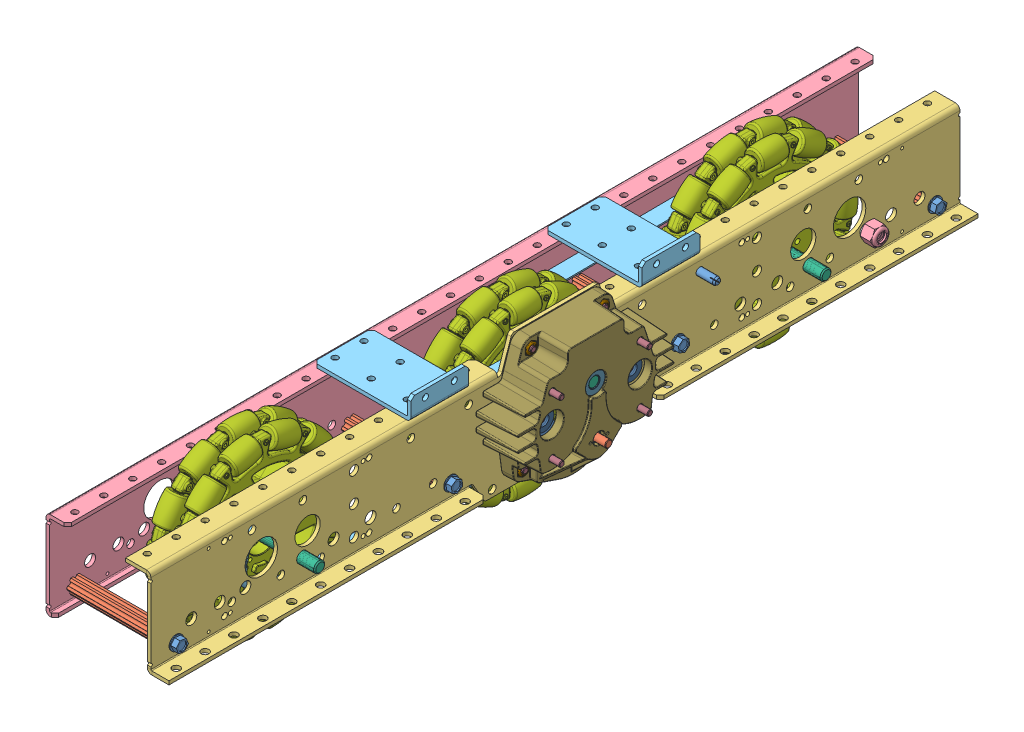
SolidWorks assembly Square half 2, configuration Default. Lengths in mm.
Overall size (145.24 217.11 711.33).
59 component instances, 25 part files, 19 mates.
Components (placement in the parent):
- AM14U3Square_Frame_Half-1: AM14U3Square_Frame_Half [Default] at (326.068 37.2757 -291.2758) size (113.54 116.33 711.33)
  - ThreadRollingScrew_0.25-20x0.75-1: ThreadRollingScrew_0.25-20x0.75 [FHTS 0.25-20-G-0.75-C] at (-758.825 -67.437 692.15) x (-1 0 0) z (0 0.924225 0.381849) size (24.64 12.19 12.19)
  - ThreadRollingScrew_0.25-20x0.75-4: ThreadRollingScrew_0.25-20x0.75 [FHTS 0.25-20-G-0.75-C] at (-758.825 -67.437 25.146) x (-1 0 0) z (0 0.717495 0.696564) size (24.64 12.19 12.19)
  - ThreadRollingScrew_0.25-20x0.75-5: ThreadRollingScrew_0.25-20x0.75 [FHTS 0.25-20-G-0.75-C] at (-850.9 -67.437 25.4) size (24.64 12.19 12.19)
  - ThreadRollingScrew_0.25-20x0.75-7: ThreadRollingScrew_0.25-20x0.75 [FHTS 0.25-20-G-0.75-C] at (-762 -15.24 231.648) x (1 0 0) z (0 0.687398 0.726281) size (24.64 12.19 12.19)
  - ThreadRollingScrew_0.25-20x0.75-9: ThreadRollingScrew_0.25-20x0.75 [FHTS 0.25-20-G-0.75-C] at (-850.9 -67.437 692.15) size (24.64 12.19 12.19)
  - 500Churro_3.375-1: 500Churro_3.375 [Default] at (-762 -67.437 25.4) x (0 -0.866025 0.5) z (-1 0 0) size (14.66 12.7 85.72)
  - 500Churro_3.375-2: 500Churro_3.375 [Default] at (-762 -67.437 692.15) x (0 -0.866025 0.5) z (-1 0 0) size (14.66 12.7 85.72)
  - AM14U3InnerPlate_Square-1: AM14U3InnerPlate_Square [Default] at (-762 -76.962 765.048) x (0 0 -1) z (0 -1 0) size (711.2 38.1 116.33)
  - AM14U3OuterPlate_Square-1: AM14U3OuterPlate_Square [Default] at (-826.4985 -26.7681 74.8245) x (0 0 1) z (0 -1 0) size (711.2 19.05 77.72)
  - Bracket_2x3-1: Bracket_2x3 [Default] at (-844.55 -3.175 498.348) size (85.72 19.05 50.8)
  - Bracket_2x3-2: Bracket_2x3 [Default] at (-844.55 -3.175 295.148) size (85.72 19.05 50.8)
  - 500Churro_3.375-5: 500Churro_3.375 [Default] at (-847.725 -66.675 450.723) x (0 0 -1) z (1 0 0) size (14.66 12.7 85.72)
  - 500Churro_3.375-6: 500Churro_3.375 [Default] at (-847.725 -59.4147 251.1225) x (0 0.13828 0.990393) z (1 0 0) size (14.66 12.7 85.72)
  - ThreadRollingScrew_0.25-20x0.75-11: ThreadRollingScrew_0.25-20x0.75 [FHTS 0.25-20-G-0.75-C] at (-758.825 -66.675 450.723) x (-1 0 0) z (0 0.997671 0.06821) size (24.64 12.19 12.19)
  - ThreadRollingScrew_0.25-20x0.75-12: ThreadRollingScrew_0.25-20x0.75 [FHTS 0.25-20-G-0.75-C] at (-758.825 -59.4147 251.1225) x (-1 0 0) z (0 -0.62596 0.779855) size (24.64 12.19 12.19)
  - ThreadRollingScrew_0.25-20x0.75-13: ThreadRollingScrew_0.25-20x0.75 [FHTS 0.25-20-G-0.75-C] at (-850.9 -66.675 450.85) size (24.64 12.19 12.19)
  - ThreadRollingScrew_0.25-20x0.75-14: ThreadRollingScrew_0.25-20x0.75 [FHTS 0.25-20-G-0.75-C] at (-850.9 -66.675 266.7) size (24.64 12.19 12.19)
- ToughboxMini-1: ToughboxMini [Default] at (-483.2987 -32.4844 158.473) x (0 0.001296 0.999999) z (-1 0 0) size (140.05 118.73 142.29) (flexible)
  - TBMiniSmallHexShaft-1: TBMiniSmallHexShaft [Default] at (-129.0775 70.1149 -52.3959) x (-0.997833 0.06579 0) z (0.06579 0.997833 0) size (11 38.23 9.52)
  - LargeClusterGear_Hex_50t0.375-1: LargeClusterGear_Hex_50t0.375 [Default] at (-91.0349 50.9043 -67.5597) x (-0.997833 0.06579 0) z (0 0 -1) size (65.97 66.04 10.16)
  - Bearing_FR6ZZ-1: Bearing_FR6ZZ [Default] at (-96.247 60.278 -52.5991) x (-0.893862 0.448342 0) z (0 0 1) size (24.69 24.69 7.16)
  - NylockNut_10-32-1: NylockNut_10-32 [Default] at (-129.8464 -8.0737 -56.3837) x (0.501678 0.865055 0) z (0 0 -1) size (10.18 11.01 7.1)
  - NylockNut_10-32-2: NylockNut_10-32 [Default] at (-59.2462 80.7349 -56.3837) x (0.999999 -0.001296 0) z (0 0 -1) size (10.18 11.01 7.1)
  - NylockNut_10-32-3: NylockNut_10-32 [Default] at (-122.7461 80.8172 -56.3837) x (0.500567 0.865698 0) z (0 0 -1) size (10.18 11.01 7.1)
  - NylockNut_10-32-4: NylockNut_10-32 [Default] at (-52.3764 -8.1741 -56.3837) x (-0.501678 -0.865055 0) z (0 0 -1) size (10.18 11.01 7.1)
  - Washer_5-16-1: Washer_5-16 [Default] at (-52.3162 38.3079 -77.7705) x (-0.418041 0.908428 0) z (0 0 -1) size (17.53 17.53 1.47)
  - Washer_5-16-2: Washer_5-16 [Default] at (-52.3162 38.3079 -76.2973) x (0.897267 -0.441488 0) z (0 0 -1) size (17.53 17.53 1.47)
  - Washer_5-16-3: Washer_5-16 [Default] at (-129.7861 38.4083 -77.7705) x (-0.990116 0.140253 0) z (0 0 1) size (17.53 17.53 1.47)
  - Washer_5-16-4: Washer_5-16 [Default] at (-129.7861 38.4083 -79.2437) x (-0.681761 0.731575 0) z (0 0 1) size (17.53 17.53 1.47)
  - CIMGear_14t8mm-1: CIMGear_14t8mm [Default] at (-52.3162 38.3079 -63.5973) x (0.300324 0.953837 0) z (0 0 -1) size (20.03 20.32 12.7)
  - CIMGear_14t8mm-2: CIMGear_14t8mm [Default] at (-129.7861 38.4083 -63.5973) x (0.860119 0.510093 0) z (0 0 -1) size (20.03 20.32 12.7)
  - TBMiniHousing-1: TBMiniHousing [Default] at (-91.0876 10.1882 -86.3557) x (0.999999 -0.001296 0) z (0 0 1) size (139.9 118.55 41.54)
  - Screw_SHCS_10-32x0.625-1: Screw_SHCS_10-32x0.625 [Default] at (-52.2832 63.7078 -74.4685) x (-0.564778 -0.825243 0) z (-0.825243 0.564778 0) size (7.82 20.65 7.82)
  - Screw_SHCS_10-32x0.625-2: Screw_SHCS_10-32x0.625 [Default] at (-122.7461 80.8172 -42.5915) x (0.507484 -0.861661 0) z (-0.861661 -0.507484 0) size (7.82 20.65 7.82)
  - Screw_SHCS_10-32x0.625-3: Screw_SHCS_10-32x0.625 [Default] at (-52.3764 -8.1741 -42.5915) x (0.507484 -0.861661 0) z (-0.861661 -0.507484 0) size (7.82 20.65 7.82)
  - Screw_SHCS_10-32x0.625-4: Screw_SHCS_10-32x0.625 [Default] at (-129.8464 -8.0737 -42.5915) x (0.507484 -0.861661 0) z (-0.861661 -0.507484 0) size (7.82 20.65 7.82)
  - Screw_SHCS_10-32x0.625-5: Screw_SHCS_10-32x0.625 [Default] at (-59.2462 80.7349 -42.5915) x (0.740711 -0.671824 0) z (-0.671824 -0.740711 0) size (7.82 20.65 7.82)
  - Screw_SHCS_10-32x0.625-6: Screw_SHCS_10-32x0.625 [Default] at (-52.3491 12.9079 -74.4685) x (-0.564778 -0.825243 0) z (-0.825243 0.564778 0) size (7.82 20.65 7.82)
  - Screw_SHCS_10-32x0.625-7: Screw_SHCS_10-32x0.625 [Default] at (-129.7532 63.8083 -74.4685) x (-0.966277 -0.257503 0) z (-0.257503 0.966277 0) size (7.82 20.65 7.82)
  - Screw_SHCS_10-32x0.625-8: Screw_SHCS_10-32x0.625 [Default] at (-129.819 13.0083 -74.4685) x (-0.99652 0.083357 0) z (0.083357 0.99652 0) size (7.82 20.65 7.82)
  - Bearing_R6ZZ-3: Bearing_R6ZZ [Default] at (-91.0349 50.9043 -84.8317) x (0.958138 -0.286306 0) z (0 0 1) size (22.23 22.23 7.11)
  - Bearing_R6ZZ-4: Bearing_R6ZZ [Default] at (-91.0876 10.1882 -84.8317) x (-0.661529 0.74992 0) z (0 0 1) size (22.23 22.23 7.11)
  - RetainingClip-1: RetainingClip [Default] at (-129.7861 38.4083 -63.5973) x (0 0 1) z (-1 0 0) size (1.09 14.83 14.83)
  - RetainingClip-2: RetainingClip [Default] at (-52.3162 38.3079 -63.5973) x (0 0 1) z (-1 0 0) size (1.09 14.83 14.83)
  - ExternalKlipring-1: ExternalKlipring [Default] at (-91.0876 10.1882 -64.4355) x (0.996411 -0.084651 0) z (0 0 1) size (19.07 20.96 1.27)
  - HexBearing_FR8ZZ-1: HexBearing_FR8ZZ [Default] at (-91.0876 10.1882 -44.6717) x (0.501122 0.865376 0) z (0 0 -1) size (31.12 31.12 7.93)
  - SmallClusterGear_Hex_16t0.375-1: SmallClusterGear_Hex_16t0.375 [Default] at (-91.0349 50.9043 -67.5597) x (0 0 1) z (-0.555893 -0.831254 0) size (15.19 22.57 22.57)
  - LargeOutputGear_Hex_48t0.5-1: LargeOutputGear_Hex_48t0.5 [Default] at (-91.0876 10.1882 -63.1655) x (0 0 1) z (-0.999999 0.001296 0) size (10.21 63.42 63.42)
  - TBMiniHexOutputShaft-2: TBMiniHexOutputShaft [Default] at (-57.4661 34.985 -52.3197) x (0.501122 0.865376 0) z (0.865376 -0.501122 0) size (14.66 142.29 12.7)
- Bearing_Hex_FR8ZZ-1: Bearing_Hex_FR8ZZ [Default] at (-528.0604 -22.4143 67.4992) x (0 -0.866025 0.5) z (1 0 0) size (31.12 31.12 7.93)
- NylockNut_0.375-16-2: NylockNut_0.375-16 [91831A127] at (-432.757 -20.8903 -208.2615) x (0 -1 0) z (0 0 1) size (14.29 12 16.5)
- Belt_15mm_Square-1: Belt_15mm_Square [Default] at (-447.8179 -20.6363 290.0469) x (0 -0.007989 -0.999968) z (-1 0 0) size (291.74 69.19 15)
- Belt_15mm_Square-2: Belt_15mm_Square [Default] at (-494.606 -20.6363 -155.0485) x (0 -0.007989 0.999968) z (-1 0 0) size (291.74 69.19 15)
- HHSBolt_0.375-16x4.25-3: HHSBolt_0.375-16x4.25 [HFBOLT 0.375-16x2.5x1-C] at (-531.0042 -20.6363 290.0469) x (1 0 0) z (0 0.54705 -0.8371) size (114.12 16.48 14.27)
- HHSBolt_0.375-16x4.25-4: HHSBolt_0.375-16x4.25 [HFBOLT 0.375-16x2.5x1-C] at (-531.0042 -20.6363 -155.0485) x (1 0 0) z (0 -0.961423 -0.275075) size (114.12 16.48 14.27)
- omniwheels-1: omniwheels [Default] at (-481.4615 -20.6363 290.0469) x (0 -0.681861 0.731482) z (0 0.731482 0.681861) size (153.62 51.4 153.62)
- omniwheels-2: omniwheels [Default] at (-478.6675 -20.6363 -155.0485) x (0 -1 0) z (0 0 1) size (153.62 51.4 153.62)
- omniwheels-3: omniwheels [Default] at (-478.9215 -28.8965 61.9348) x (0 -1 0.000016) z (0 0.000016 1) size (153.62 51.4 153.62)
Mates (geometry in assembly coordinates):
- Concentric1: concentric anti-aligned: cylinder of ToughboxMini-1/HexBearing_FR8ZZ-1 through (-430.6996 -22.4143 67.3722) axis (-1 0 0) radius 14.2875; cylinder of AM14U3Square_Frame_Half-1/AM14U3InnerPlate_Square-1 through (-435.932 -22.4143 67.3722) axis (1 0 0) radius 14.2875
- Parallel1: parallel: line of ToughboxMini-1/TBMiniHousing-1 through (-432.2313 57.1529 35.6222) axis (0 0 1); plane of AM14U3Square_Frame_Half-1/AM14U3InnerPlate_Square-1 through (-432.757 57.5957 19.7472) normal (0 1 0)
- Coincident2: coincident anti-aligned: plane of AM14U3Square_Frame_Half-1/AM14U3InnerPlate_Square-1 through (-432.757 30.1637 473.7722) normal (1 0 0); plane of ToughboxMini-1/TBMiniHousing-1 through (-432.757 -22.4143 67.3722) normal (-1 0 0)
- Concentric51: concentric aligned: cylinder of AM14U3Square_Frame_Half-1/AM14U3OuterPlate_Square-1 through (-521.657 -22.4143 67.4992) axis (-1 0 0) radius 14.2875; cylinder of Bearing_Hex_FR8ZZ-1 through (-520.133 -22.4143 67.4992) axis (-1 0 0) radius 13.97
- Coincident71: coincident anti-aligned: plane of AM14U3Square_Frame_Half-1/AM14U3OuterPlate_Square-1 through (-521.657 30.1637 -338.9008) normal (1 0 0); plane of Bearing_Hex_FR8ZZ-1 through (-521.657 -34.5127 74.4842) normal (-1 0 0)
- Coincident8: coincident anti-aligned: plane of ToughboxMini-1/TBMiniHexOutputShaft-2 through (-405.579 -28.7643 63.706) normal (0 -1 0); plane of Bearing_Hex_FR8ZZ-1 through (-520.133 -28.7643 63.833) normal (0 1 0)
- Coincident12: coincident anti-aligned: plane of AM14U3Square_Frame_Half-1/AM14U3InnerPlate_Square-1 through (-432.757 30.1637 473.7722) normal (1 0 0); plane of NylockNut_0.375-16-2 through (-432.757 -13.7466 -220.6349) normal (-1 0 0)
- Concentric12: concentric anti-aligned: cylinder of Bearing_Hex_FR8ZZ-1 through (-520.133 -22.4143 67.4992) axis (-1 0 0) radius 14.2875; cylinder of Belt_15mm_Square-1 through (-462.8179 -22.4143 67.4992) axis (1 0 0) radius 33.4264
- Concentric13: concentric anti-aligned: cylinder of Bearing_Hex_FR8ZZ-1 through (-520.133 -22.4143 67.4992) axis (-1 0 0) radius 14.2875; cylinder of Belt_15mm_Square-2 through (-509.606 -22.4143 67.4992) axis (1 0 0) radius 33.4264
- Concentric72: concentric aligned: cylinder of AM14U3Square_Frame_Half-1/AM14U3OuterPlate_Square-1 through (-413.706 -20.6363 290.0469) axis (-1 0 0) radius 4.826; cylinder of HHSBolt_0.375-16x4.25-3 through (-531.0042 -20.6363 290.0469) axis (-1 0 0) radius 4.7625
- Coincident102: coincident anti-aligned: plane of AM14U3Square_Frame_Half-1/AM14U3OuterPlate_Square-1 through (-524.832 30.1637 -338.9008) normal (-1 0 0); plane of HHSBolt_0.375-16x4.25-3 through (-524.832 -27.5353 285.5383) normal (1 0 0)
- Concentric731: concentric aligned: cylinder of AM14U3Square_Frame_Half-1/AM14U3OuterPlate_Square-1 through (-413.706 -20.6363 -155.0485) axis (-1 0 0) radius 4.826; cylinder of HHSBolt_0.375-16x4.25-4 through (-531.0042 -20.6363 -155.0485) axis (-1 0 0) radius 7.1374
- Coincident1031: coincident anti-aligned: plane of AM14U3Square_Frame_Half-1/AM14U3OuterPlate_Square-1 through (-524.832 30.1637 -338.9008) normal (-1 0 0); plane of HHSBolt_0.375-16x4.25-4 through (-524.832 -22.9034 -147.1249) normal (1 0 0)
- Concentric732: concentric anti-aligned: cylinder of HHSBolt_0.375-16x4.25-3 through (-531.0042 -20.6363 290.0469) axis (-1 0 0) radius 4.7625; cylinder of omniwheels-1 through (-471.9365 -20.6363 290.0469) axis (1 0 0) radius 14.3
- Distance1: distance = 25.908 mm anti-aligned: plane of AM14U3Square_Frame_Half-1/AM14U3OuterPlate_Square-1 through (-521.657 30.1637 -338.9008) normal (1 0 0); plane of omniwheels-1 through (-495.749 -20.6363 290.0469) normal (-1 0 0)
- Concentric733: concentric anti-aligned: cylinder of HHSBolt_0.375-16x4.25-4 through (-531.0042 -20.6363 -155.0485) axis (-1 0 0) radius 4.7625; cylinder of omniwheels-2 through (-469.1425 -20.6363 -155.0485) axis (1 0 0) radius 14.3
- Distance2: distance = 28.702 mm anti-aligned: plane of AM14U3Square_Frame_Half-1/AM14U3OuterPlate_Square-1 through (-521.657 30.1637 -338.9008) normal (1 0 0); plane of omniwheels-2 through (-492.955 -20.6363 -155.0485) normal (-1 0 0)
- Tangent1: tangent aligned: plane of ToughboxMini-1/TBMiniHexOutputShaft-2 through (-405.579 -22.4143 74.7045) normal (0 0.5 0.866025); cylinder of omniwheels-3 through (-469.3965 -28.8965 61.9348) axis (1 0 0) radius 14.3
- Distance3: distance = 28.702 mm anti-aligned: plane of omniwheels-3 through (-464.634 -28.8965 61.9348) normal (1 0 0); plane of AM14U3Square_Frame_Half-1/AM14U3InnerPlate_Square-1 through (-435.932 30.1637 473.7722) normal (-1 0 0)
